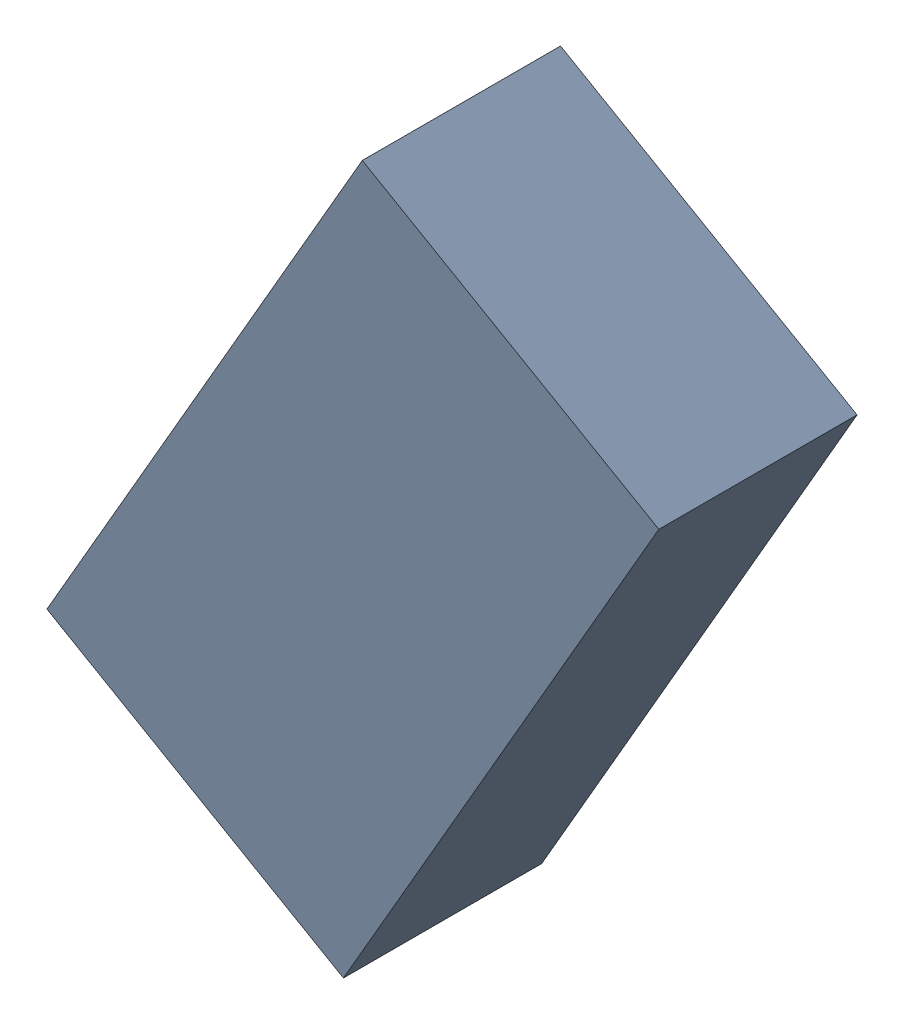
SolidWorks assembly L4_TDA3, configuration Standard. Lengths in mm.
Overall size (1.7 1.99 0.55).
2 component instances, 1 part files, 0 mates.
Components (placement in the parent):
- 885543600-1: 885543600 [Standard] at (49.9698 -31.5411 0) size (1.7 1.99 0.55)
  - Extruded_17-1: Extruded_17 [Standard] at origin size (1.7 1.99 0.55)
